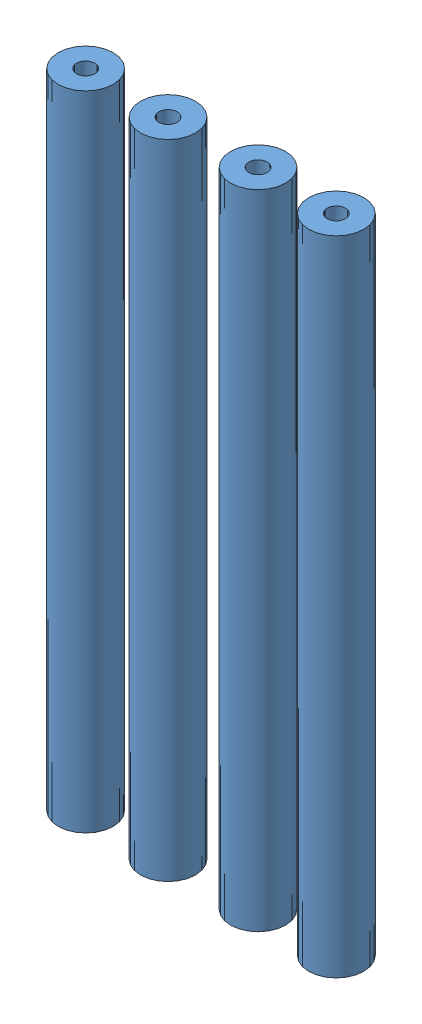
SolidWorks assembly Columnas_CHASIS_BOVER, configuration Predeterminado. Lengths in mm.
Overall size (33.44 70.3 7.38).
4 component instances, 1 part files, 0 mates.
Components (placement in the parent):
- Columnas_ChasisLaberinto-2: Columnas_ChasisLaberinto [Predeterminado] at (-18.3717 -33.6384 69.6997) x (0.963752 0 -0.266801) z (0.266801 0 0.963752) size (6 70 6)
- Columnas_ChasisLaberinto-3: Columnas_ChasisLaberinto [Predeterminado] at (-30.3665 -33.8356 69.9732) x (0.999981 0 -0.006167) z (0.006167 0 0.999981) size (6 70 6)
- Columnas_ChasisLaberinto-4: Columnas_ChasisLaberinto [Predeterminado] at (-39.5316 -33.9343 69.7773) x (0.999981 0 -0.006167) z (0.006167 0 0.999981) size (6 70 6)
- Columnas_ChasisLaberinto-5: Columnas_ChasisLaberinto [Predeterminado] at (-12.1568 -33.8329 69.9021) size (6 70 6)
